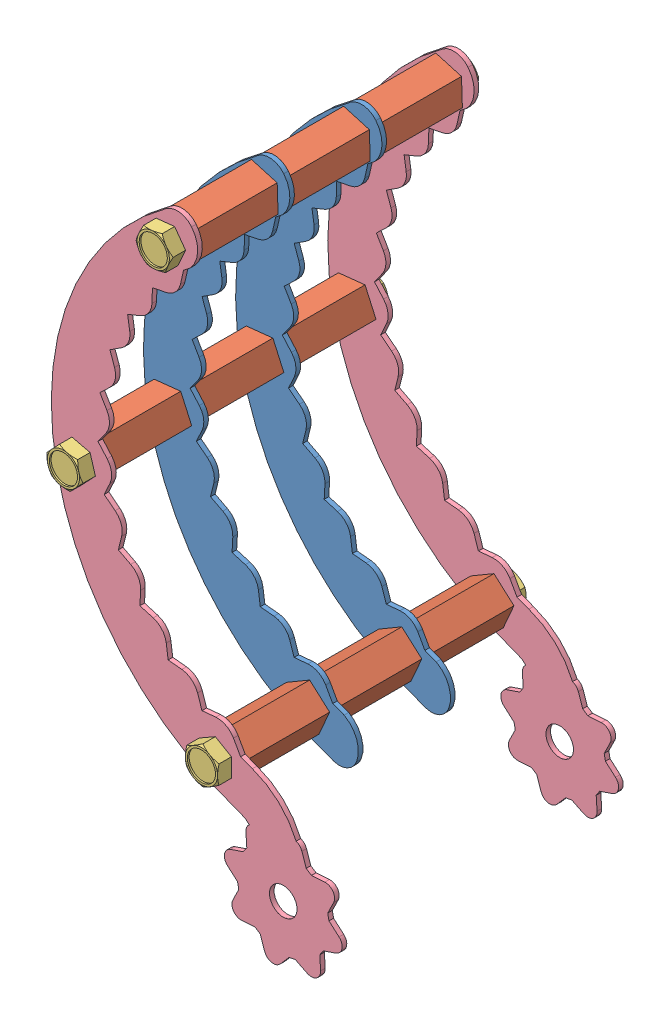
SolidWorks assembly kıskac1-montaj, configuration Varsayılan. Lengths in mm.
Overall size (71.92 139.22 67).
19 component instances, 4 part files, 26 mates.
Components (placement in the parent):
- kiskac2-1: kiskac2 [Varsayılan] at (-33.2423 -8.3024 150.4684) x (0.98838 0.152004 0) z (0 0 1) size (38.9 107.85 1)
- kiskac2-2: kiskac2 [Varsayılan] at (-33.2423 -8.3024 170.4684) x (0.98838 0.152004 0) z (0 0 1) size (38.9 107.85 1)
- araparca-1: araparca [Varsayılan] at (-57.6545 -57.5877 171.4684) x (0.999973 -0.007287 0) z (0 0 1) size (9.37 9.17 19)
- araparca-2: araparca [Varsayılan] at (-57.6545 -57.5877 151.4684) x (0.999973 -0.007287 0) z (0 0 1) size (9.37 9.17 19)
- araparca-3: araparca [Varsayılan] at (-57.6545 -57.5877 131.4684) x (0.999973 -0.007287 0) z (0 0 1) size (9.37 9.17 19)
- araparca-4: araparca [Varsayılan] at (-87.6032 -16.6626 171.4684) x (-0.115596 -0.993296 0) z (0 0 1) size (9.37 9.17 19)
- araparca-5: araparca [Varsayılan] at (-68.1133 34.2302 171.4684) x (-0.124015 0.99228 0) z (0 0 1) size (9.37 9.17 19)
- araparca-6: araparca [Varsayılan] at (-87.6032 -16.6626 151.4684) x (-0.115596 -0.993296 0) z (0 0 1) size (9.37 9.17 19)
- araparca-7: araparca [Varsayılan] at (-87.6032 -16.6626 131.4684) x (-0.115596 -0.993296 0) z (0 0 1) size (9.37 9.17 19)
- araparca-8: araparca [Varsayılan] at (-68.1133 34.2302 151.4684) x (-0.124015 0.99228 0) z (0 0 1) size (9.37 9.17 19)
- araparca-9: araparca [Varsayılan] at (-68.1133 34.2302 131.4684) x (-0.124015 0.99228 0) z (0 0 1) size (9.37 9.17 19)
- hex screw_am-2: hex screw_am [B18.6.7M - M4 x 0.7 x 30 Indented HHMS --30N] at (-57.6545 -57.5877 127.4684) x (0 0 1) z (1 0 0) size (33 8.08 7)
- hex screw_am-4: hex screw_am [B18.6.7M - M4 x 0.7 x 30 Indented HHMS --30N] at (-68.1133 34.2302 127.4684) x (0 0 1) z (0.685884 0.727711 0) size (33 8.08 7)
- hex screw_am-5: hex screw_am [B18.6.7M - M4 x 0.7 x 30 Indented HHMS --30N] at (-68.1133 34.2302 194.4684) x (0 0 -1) z (0.808153 0.588972 0) size (33 8.08 7)
- hex screw_am-6: hex screw_am [B18.6.7M - M4 x 0.7 x 30 Indented HHMS --30N] at (-87.6032 -16.6626 194.4684) x (0 0 -1) z (-0.726403 0.687269 0) size (33 8.08 7)
- hex screw_am-7: hex screw_am [B18.6.7M - M4 x 0.7 x 30 Indented HHMS --30N] at (-57.6545 -57.5877 194.4684) x (0 0 -1) z (0.502869 0.864363 0) size (33 8.08 7)
- hex screw_am-8: hex screw_am [B18.6.7M - M4 x 0.7 x 30 Indented HHMS --30N] at (-87.6032 -16.6626 127.4684) x (0 0 1) z (0.726403 -0.687269 0) size (33 8.08 7)
- kiskac1-sol-1: kiskac1-sol [Varsayılan] at (-33.2423 -8.3024 130.4684) x (0.98838 0.152004 0) z (0 0 1) size (52.34 132.8 1)
- kiskac1-sol-2: kiskac1-sol [Varsayılan] at (-33.2423 -8.3024 190.4684) x (0.98838 0.152004 0) z (0 0 1) size (52.34 132.8 1)
Mates (geometry in assembly coordinates):
- Eş Merkezli3: concentric aligned: circle of kiskac2-1; circle of kiskac2-2
- Eş Merkezli4: concentric aligned: circle of kiskac2-1; circle of kiskac2-2
- Uzaklık2: distance = 19 mm anti-aligned: plane of kiskac2-2 through (-69.1259 28.5299 170.4684) normal (0 0 -1); plane of kiskac2-1 through (-69.1259 28.5299 151.4684) normal (0 0 1)
- Eş Merkezli5: concentric aligned: cylinder of kiskac2-1 through (-68.1133 34.2302 151.4684) axis (0 0 -1) radius 2.5; cylinder of kiskac2-2 through (-68.1133 34.2302 171.4684) axis (0 0 -1) radius 2.5
- Eş Merkezli6: concentric aligned: cylinder of kiskac2-1 through (-87.6032 -16.6626 151.4684) axis (0 0 -1) radius 2.5; cylinder of kiskac2-2 through (-87.6032 -16.6626 171.4684) axis (0 0 -1) radius 2.5
- Eş Merkezli10: concentric aligned: cylinder of kiskac2-2 through (-87.6032 -16.6626 171.4684) axis (0 0 -1) radius 2.5; cylinder of araparca-4 through (-87.6032 -16.6626 190.4684) axis (0 0 -1) radius 2.5
- Çakışık10: coincident anti-aligned: plane of kiskac2-2 through (-69.1259 28.5299 171.4684) normal (0 0 1); plane of araparca-4 through (-87.6032 -16.6626 171.4684) normal (0 0 -1)
- Eş Merkezli11: concentric aligned: cylinder of kiskac2-2 through (-68.1133 34.2302 171.4684) axis (0 0 -1) radius 2.5; cylinder of araparca-5 through (-68.1133 34.2302 190.4684) axis (0 0 -1) radius 2.5
- Çakışık12: coincident anti-aligned: plane of kiskac2-2 through (-69.1259 28.5299 171.4684) normal (0 0 1); plane of araparca-5 through (-68.1133 34.2302 171.4684) normal (0 0 -1)
- Eş Merkezli12: concentric aligned: cylinder of hex screw_am-2 through (-57.6545 -57.5877 102.0684) axis (0 0 -1) radius 2; cylinder of kiskac1-sol-1 through (-57.6545 -57.5877 131.4684) axis (0 0 -1) radius 2.5
- Çakışık13: coincident anti-aligned: plane of hex screw_am-2 through (-57.6545 -59.5877 130.4684) normal (0 0 1); plane of kiskac1-sol-1 through (-69.1259 28.5299 130.4684) normal (0 0 -1)
- Eş Merkezli13: concentric aligned: cylinder of hex screw_am-8 through (-87.6032 -16.6626 102.0684) axis (0 0 -1) radius 2; cylinder of kiskac1-sol-1 through (-87.6032 -16.6626 131.4684) axis (0 0 -1) radius 2.5
- Eş Merkezli14: concentric aligned: cylinder of kiskac2-1 through (-87.6032 -16.6626 151.4684) axis (0 0 -1) radius 2.5; cylinder of hex screw_am-8 through (-87.6032 -16.6626 102.0684) axis (0 0 -1) radius 2
- Eş Merkezli15: concentric aligned: cylinder of araparca-3 through (-57.6545 -57.5877 150.4684) axis (0 0 -1) radius 2.5; cylinder of hex screw_am-2 through (-57.6545 -57.5877 102.0684) axis (0 0 -1) radius 2
- Çakışık15: coincident anti-aligned: plane of araparca-3 through (-57.6545 -57.5877 131.4684) normal (0 0 -1); plane of kiskac1-sol-1 through (-69.1259 28.5299 131.4684) normal (0 0 1)
- Çakışık16: coincident anti-aligned: plane of hex screw_am-8 through (-88.9777 -18.1154 130.4684) normal (0 0 1); plane of kiskac1-sol-1 through (-69.1259 28.5299 130.4684) normal (0 0 -1)
- Eş Merkezli16: concentric aligned: cylinder of kiskac2-1 through (-87.6032 -16.6626 151.4684) axis (0 0 -1) radius 2.5; cylinder of kiskac1-sol-1 through (-87.6032 -16.6626 131.4684) axis (0 0 -1) radius 2.5
- Çakışık17: coincident anti-aligned: plane of kiskac2-2 through (-69.1259 28.5299 171.4684) normal (0 0 1); plane of araparca-1 through (-57.6545 -57.5877 171.4684) normal (0 0 -1)
- Eş Merkezli17: concentric aligned: cylinder of kiskac2-2 through (-57.6545 -57.5877 171.4684) axis (0 0 -1) radius 2.5; cylinder of araparca-1 through (-57.6545 -57.5877 190.4684) axis (0 0 -1) radius 2.5
- Eş Merkezli19: concentric aligned: cylinder of hex screw_am-4 through (-68.1133 34.2302 102.0684) axis (0 0 -1) radius 2; cylinder of kiskac1-sol-1 through (-68.1133 34.2302 131.4684) axis (0 0 -1) radius 2.5
- Çakışık18: coincident anti-aligned: plane of hex screw_am-4 through (-66.6578 32.8584 130.4684) normal (0 0 1); plane of kiskac1-sol-1 through (-69.1259 28.5299 130.4684) normal (0 0 -1)
- Uzaklık5: distance = 1 mm anti-aligned: plane of hex screw_am-5 through (-69.2912 35.8465 191.4684) normal (0 0 -1); plane of araparca-5 through (-68.1133 34.2302 190.4684) normal (0 0 1)
- Eş Merkezli21: concentric anti-aligned: cylinder of araparca-5 through (-68.1133 34.2302 190.4684) axis (0 0 -1) radius 2.5; cylinder of hex screw_am-5 through (-68.1133 34.2302 219.8684) axis (0 0 1) radius 2
- Uzaklık6: distance = 1 mm anti-aligned: plane of hex screw_am-6 through (-88.9777 -18.1154 191.4684) normal (0 0 -1); plane of araparca-4 through (-87.6032 -16.6626 190.4684) normal (0 0 1)
- Uzaklık7: distance = 1 mm anti-aligned: plane of hex screw_am-7 through (-59.3832 -56.582 191.4684) normal (0 0 -1); plane of araparca-1 through (-57.6545 -57.5877 190.4684) normal (0 0 1)
- Eş Merkezli22: concentric anti-aligned: cylinder of araparca-1 through (-57.6545 -57.5877 190.4684) axis (0 0 -1) radius 2.5; cylinder of hex screw_am-7 through (-57.6545 -57.5877 219.8684) axis (0 0 1) radius 2
